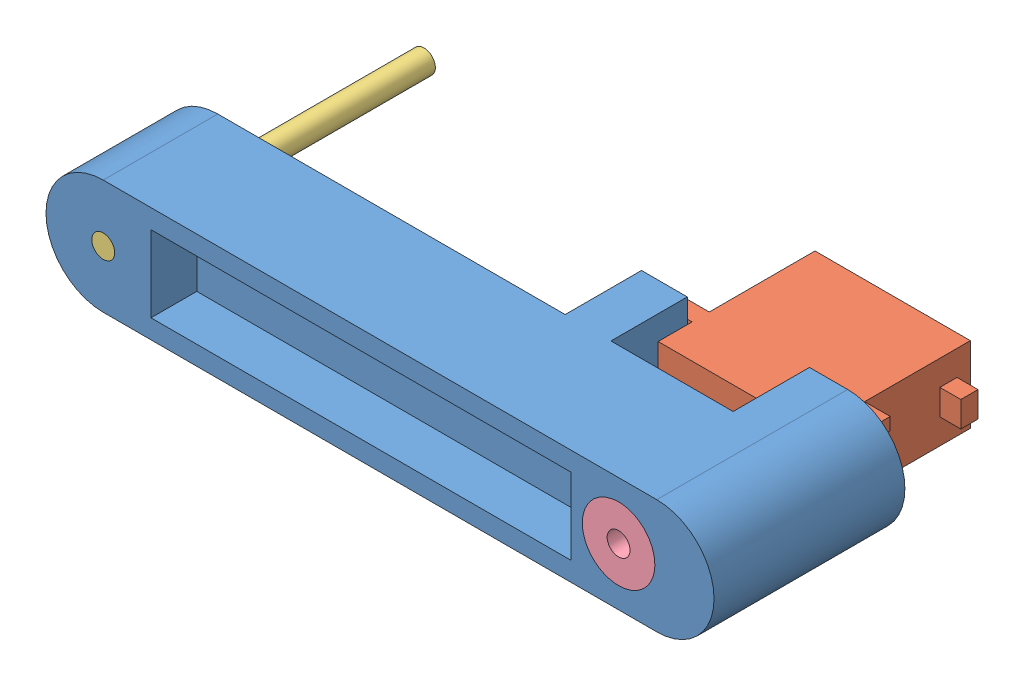
SolidWorks assembly Assem3, configuration Default. Lengths in mm.
Overall size (175 30 84).
5 component instances, 4 part files, 7 mates.
Components (placement in the parent):
- link2-1: link2 [Default] at (-76.8732 116.6216 178.9186) size (175 30 50)
- motor-1: motor [Default] at (47.7268 116.6216 96.7186) x (-1 0 0) z (0 0 1) size (54.1 19.9 44.8)
- shaft2-1: shaft2 [Default] at (-76.8732 116.6216 94.9186) size (6 6 84)
- Bearing-1: Bearing [Default] at (58.1268 116.6216 178.9186) x (1 0 0) z (0 1 0) size (19 6 19)
- Bearing-2: Bearing [Default] at (58.1268 116.6216 154.9186) x (1 0 0) z (0 1 0) size (19 6 19)
Mates (geometry in assembly coordinates):
- Coincident1: coincident anti-aligned: circle of link2-1; circle of Bearing-1
- Coincident2: coincident aligned: circle of link2-1; circle of Bearing-2
- Coincident3: coincident aligned: circle of link2-1; circle of shaft2-1
- Parallel1: parallel anti-aligned: plane of link2-1 through (-76.8732 116.6216 148.9186) normal (0 0 -1); plane of motor-1 through (47.7268 116.6216 137.8186) normal (0 0 1)
- Concentric3: concentric anti-aligned: circle of link2-1; circle of motor-1
- Concentric4: concentric anti-aligned: circle of link2-1; circle of motor-1
- Coincident8: coincident anti-aligned: plane of link2-1 through (-76.8732 101.6216 128.9186) normal (0 0 -1); plane of motor-1 through (74.7768 52.3848 128.9186) normal (0 0 1)
